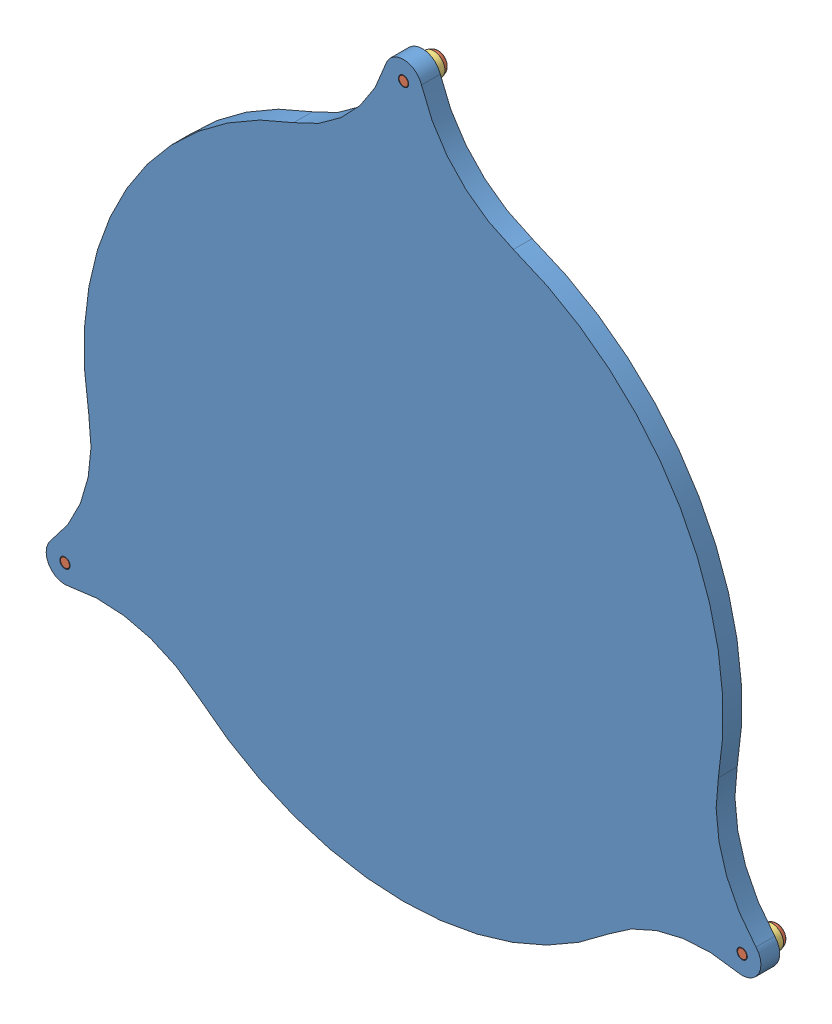
SolidWorks assembly bed-assy, configuration Default. Lengths in mm.
Overall size (190.13 194 9.65).
7 component instances, 3 part files, 12 mates.
Components (placement in the parent):
- 1287-1: 1287 [Default] at (-8.7017 8.1778 0) size (190.13 194 5)
- 1137-1: 1137 [Default] at (-98.7683 -43.8222 -3) x (-0.414013 0.910271 0) z (0 0 -1) size (5.7 5.7 9.65)
- 1137-2: 1137 [Default] at (81.365 -43.8222 -3) x (0.972431 0.233189 0) z (0 0 -1) size (5.7 5.7 9.65)
- 1137-3: 1137 [Default] at (-8.7017 112.1778 -3) x (-0.178431 -0.983952 0) z (0 0 -1) size (5.7 5.7 9.65)
- 1298-1: 1298 [Default] at (-8.7017 112.1778 -3) size (6 6 3)
- 1298-2: 1298 [Default] at (81.365 -43.8222 -3) size (6 6 3)
- 1298-3: 1298 [Default] at (-98.7683 -43.8222 -3) size (6 6 3)
Mates (geometry in assembly coordinates):
- Concentric47: concentric aligned: cylinder of 1287-1 through (-8.7017 112.1778 5) axis (0 0 -1) radius 1.375; cylinder of 1137-3 through (-8.7017 112.1778 5) axis (0 0 -1) radius 1.5
- Concentric48: concentric aligned: cylinder of 1287-1 through (81.365 -43.8222 5) axis (0 0 -1) radius 1.375; cylinder of 1137-2 through (81.365 -43.8222 5) axis (0 0 -1) radius 1.5
- Concentric49: concentric aligned: cylinder of 1287-1 through (-98.7683 -43.8222 5) axis (0 0 -1) radius 1.375; cylinder of 1137-1 through (-98.7683 -43.8222 5) axis (0 0 -1) radius 1.5
- Coincident47: coincident anti-aligned: plane of 1287-1 through (12.78 66.8701 0) normal (0 0 -1); plane of 1298-1 through (-8.7017 112.1778 0) normal (0 0 1)
- Concentric50: concentric aligned: cylinder of 1137-3 through (-8.7017 112.1778 5) axis (0 0 -1) radius 1.5; cylinder of 1298-1 through (-8.7017 112.1778 0) axis (0 0 -1) radius 1.5
- Coincident48: coincident anti-aligned: plane of 1137-3 through (-8.7017 112.1778 -3) normal (0 0 1); plane of 1298-1 through (-8.7017 112.1778 -3) normal (0 0 -1)
- Coincident49: coincident anti-aligned: plane of 1287-1 through (12.78 66.8701 0) normal (0 0 -1); plane of 1298-3 through (-98.7683 -43.8222 0) normal (0 0 1)
- Coincident50: coincident anti-aligned: plane of 1287-1 through (12.78 66.8701 0) normal (0 0 -1); plane of 1298-2 through (81.365 -43.8222 0) normal (0 0 1)
- Concentric51: concentric aligned: cylinder of 1298-2 through (81.365 -43.8222 0) axis (0 0 -1) radius 1.5; cylinder of 1137-2 through (81.365 -43.8222 5) axis (0 0 -1) radius 1.5
- Concentric52: concentric aligned: cylinder of 1137-1 through (-98.7683 -43.8222 5) axis (0 0 -1) radius 1.5; cylinder of 1298-3 through (-98.7683 -43.8222 0) axis (0 0 -1) radius 1.5
- Coincident51: coincident anti-aligned: plane of 1137-1 through (-98.7683 -43.8222 -3) normal (0 0 1); plane of 1298-3 through (-98.7683 -43.8222 -3) normal (0 0 -1)
- Coincident52: coincident anti-aligned: plane of 1137-2 through (81.365 -43.8222 -3) normal (0 0 1); plane of 1298-2 through (81.365 -43.8222 -3) normal (0 0 -1)
